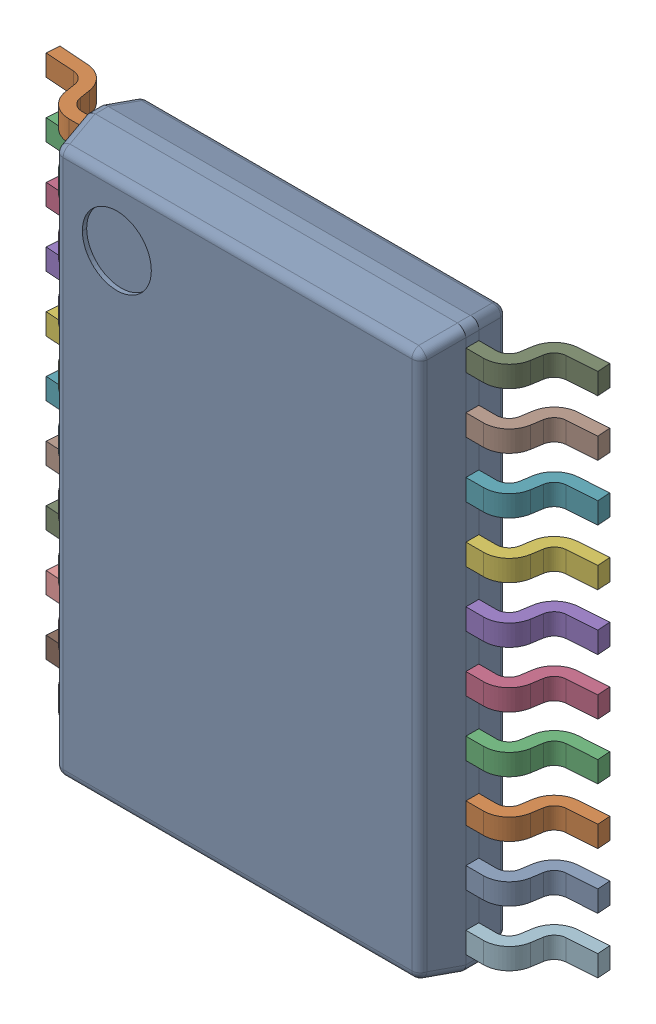
SolidWorks assembly 9651432272_1.step, configuration Default. Lengths in mm.
Overall size (6.4 6.5 1.13).
21 component instances, 2 part files, 0 mates.
Components (placement in the parent):
- BODY-TSSOP_1.step-3: BODY-TSSOP_1.step [Default] at (0 0 0.68) x (1 0 0) z (0 -1 0) size (4.4 1 6.5)
- LEAD-TSSOP_1.step-66: LEAD-TSSOP_1.step [Default] at (-2.575 2.925 0.25) x (0 -1 0) z (-1 0 0) size (0.24 0.68 1)
- LEAD-TSSOP_1.step-67: LEAD-TSSOP_1.step [Default] at (-2.575 2.275 0.25) x (0 -1 0) z (-1 0 0) size (0.24 0.68 1)
- LEAD-TSSOP_1.step-68: LEAD-TSSOP_1.step [Default] at (-2.575 1.625 0.25) x (0 -1 0) z (-1 0 0) size (0.24 0.68 1)
- LEAD-TSSOP_1.step-69: LEAD-TSSOP_1.step [Default] at (-2.575 0.975 0.25) x (0 -1 0) z (-1 0 0) size (0.24 0.68 1)
- LEAD-TSSOP_1.step-70: LEAD-TSSOP_1.step [Default] at (-2.575 0.325 0.25) x (0 -1 0) z (-1 0 0) size (0.24 0.68 1)
- LEAD-TSSOP_1.step-71: LEAD-TSSOP_1.step [Default] at (-2.575 -0.325 0.25) x (0 -1 0) z (-1 0 0) size (0.24 0.68 1)
- LEAD-TSSOP_1.step-72: LEAD-TSSOP_1.step [Default] at (-2.575 -0.975 0.25) x (0 -1 0) z (-1 0 0) size (0.24 0.68 1)
- LEAD-TSSOP_1.step-73: LEAD-TSSOP_1.step [Default] at (-2.575 -1.625 0.25) x (0 -1 0) z (-1 0 0) size (0.24 0.68 1)
- LEAD-TSSOP_1.step-74: LEAD-TSSOP_1.step [Default] at (-2.575 -2.275 0.25) x (0 -1 0) z (-1 0 0) size (0.24 0.68 1)
- LEAD-TSSOP_1.step-75: LEAD-TSSOP_1.step [Default] at (-2.575 -2.925 0.25) x (0 -1 0) z (-1 0 0) size (0.24 0.68 1)
- LEAD-TSSOP_1.step-76: LEAD-TSSOP_1.step [Default] at (2.575 -2.925 0.25) x (0 1 0) z (1 0 0) size (0.24 0.68 1)
- LEAD-TSSOP_1.step-77: LEAD-TSSOP_1.step [Default] at (2.575 -2.275 0.25) x (0 1 0) z (1 0 0) size (0.24 0.68 1)
- LEAD-TSSOP_1.step-78: LEAD-TSSOP_1.step [Default] at (2.575 -1.625 0.25) x (0 1 0) z (1 0 0) size (0.24 0.68 1)
- LEAD-TSSOP_1.step-79: LEAD-TSSOP_1.step [Default] at (2.575 -0.975 0.25) x (0 1 0) z (1 0 0) size (0.24 0.68 1)
- LEAD-TSSOP_1.step-80: LEAD-TSSOP_1.step [Default] at (2.575 -0.325 0.25) x (0 1 0) z (1 0 0) size (0.24 0.68 1)
- LEAD-TSSOP_1.step-81: LEAD-TSSOP_1.step [Default] at (2.575 0.325 0.25) x (0 1 0) z (1 0 0) size (0.24 0.68 1)
- LEAD-TSSOP_1.step-82: LEAD-TSSOP_1.step [Default] at (2.575 0.975 0.25) x (0 1 0) z (1 0 0) size (0.24 0.68 1)
- LEAD-TSSOP_1.step-83: LEAD-TSSOP_1.step [Default] at (2.575 1.625 0.25) x (0 1 0) z (1 0 0) size (0.24 0.68 1)
- LEAD-TSSOP_1.step-84: LEAD-TSSOP_1.step [Default] at (2.575 2.275 0.25) x (0 1 0) z (1 0 0) size (0.24 0.68 1)
- LEAD-TSSOP_1.step-85: LEAD-TSSOP_1.step [Default] at (2.575 2.925 0.25) x (0 1 0) z (1 0 0) size (0.24 0.68 1)
